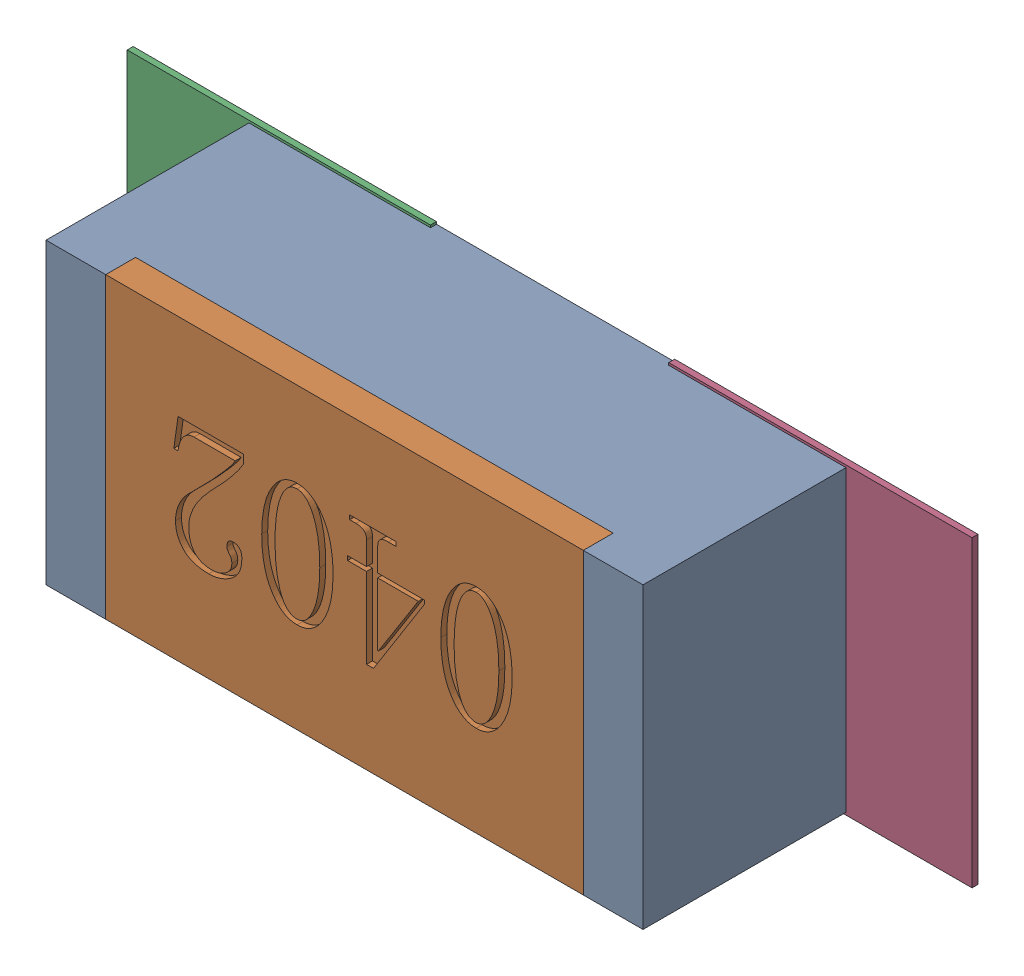
SolidWorks assembly R19, configuration Défaut. Lengths in mm.
Overall size (1.42 0.51 0.35).
5 component instances, 2 part files, 0 mates.
Components (placement in the parent):
- R0402-1: R0402 [Défaut] at (53.8662 -10.9347 0) x (-1 0 0) z (0 0 1) size (1 0.5 0.35)
- 6504207776-1: 6504207776 [Défaut] at (53.4162 -10.9348 0) size (0.51 0.51 0.01)
  - Extruded-1: Extruded [Défaut] at origin size (0.51 0.51 0.01)
- 6504207776-2: 6504207776 [Défaut] at (54.3233 -10.9348 0) size (0.51 0.51 0.01)
  - Extruded-1: Extruded [Défaut] at origin size (0.51 0.51 0.01)
